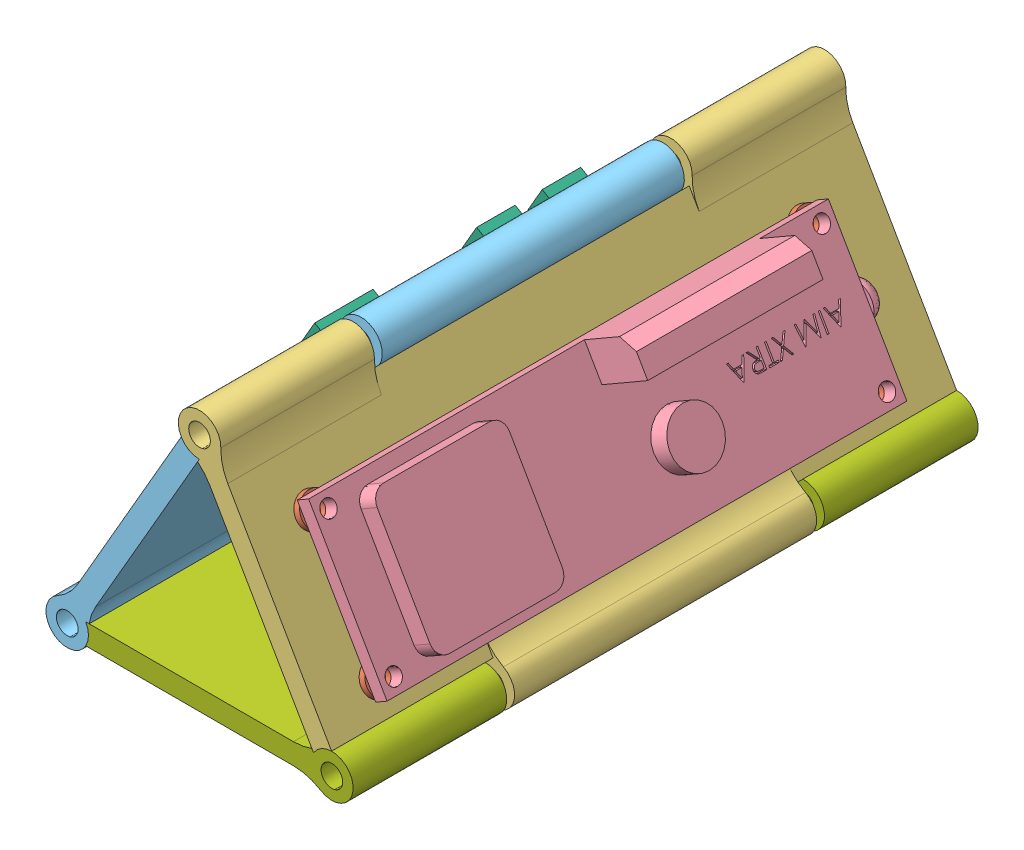
SolidWorks assembly S1B_Fight_Computer_Stack_Assy, configuration Default. Lengths in mm.
Overall size (74.68 77.18 120).
30 component instances, 8 part files, 70 mates.
Components (placement in the parent):
- S1B_6.86mm_Nut_3mm_Hole-7: S1B_6.86mm_Nut_3mm_Hole [Default] at (49.4605 62.5264 50.3494) x (0.433013 -0.75 0.5) z (-0.25 0.433013 0.866025) size (7.92 1.91 6.86)
- S1B_6.86mm_Nut_3mm_Hole-10: S1B_6.86mm_Nut_3mm_Hole [Default] at (38.5881 85.168 145.066) x (-0.433013 0.75 -0.5) z (-0.25 0.433013 0.866025) size (7.92 1.91 6.86)
- S1B_6.86mm_Nut_3mm_Hole-11: S1B_6.86mm_Nut_3mm_Hole [Default] at (36.9383 84.2155 50.3494) x (0.433013 -0.75 -0.5) z (0.25 -0.433013 0.866025) size (7.92 1.91 6.86)
- S1B_6.86mm_Nut_3mm_Hole-12: S1B_6.86mm_Nut_3mm_Hole [Default] at (49.4605 62.5264 145.066) x (0.433013 -0.75 -0.5) z (0.25 -0.433013 0.866025) size (7.92 1.91 6.86)
- S1B_Ruber_Washer_3mm-5: S1B_Ruber_Washer_3mm [Default] at (53.7083 64.9789 145.066) x (-0.5 0.866025 0) z (0 0 1) size (6 1.25 6)
- S1B_Ruber_Washer_3mm-6: S1B_Ruber_Washer_3mm [Default] at (41.1861 86.668 145.066) x (-0.5 0.866025 0) z (0 0 1) size (6 1.25 6)
- S1B_Ruber_Washer_3mm-7: S1B_Ruber_Washer_3mm [Default] at (53.7083 64.9789 50.3494) x (-0.5 0.866025 0) z (0 0 1) size (6 1.25 6)
- S1B_Ruber_Washer_3mm-8: S1B_Ruber_Washer_3mm [Default] at (41.1861 86.668 50.3494) x (-0.5 0.866025 0) z (0 0 1) size (6 1.25 6)
- S1B_Avionics_Stack - AIM-1: S1B_Avionics_Stack - AIM [Default] at (55.5493 84.6273 26.5774) x (-0.5 -0.866025 0) z (0 0 1) size (33.58 52.18 120)
- S1B_AimXtra-1: S1B_AimXtra [Default] at (39.9161 88.8677 47.8094) x (0 0 1) z (-0.5 0.866025 0) size (102.34 16.13 30.12)
- S1B_6.86mm_Nut_3mm_Hole-13: S1B_6.86mm_Nut_3mm_Hole [Default] at (13.2223 66.1787 125.5587) x (0.433013 0.75 -0.5) z (0.25 0.433013 0.866025) size (7.92 1.91 6.86)
- S1B_6.86mm_Nut_3mm_Hole-14: S1B_6.86mm_Nut_3mm_Hole [Default] at (24.7223 86.0973 125.5587) x (0.433013 0.75 -0.5) z (0.25 0.433013 0.866025) size (7.92 1.91 6.86)
- S1B_6.86mm_Nut_3mm_Hole-15: S1B_6.86mm_Nut_3mm_Hole [Default] at (13.2223 66.1787 69.0624) x (0.433013 0.75 0.5) z (-0.25 -0.433013 0.866025) size (7.92 1.91 6.86)
- S1B_6.86mm_Nut_3mm_Hole-16: S1B_6.86mm_Nut_3mm_Hole [Default] at (24.7223 86.0973 67.5587) x (0.433013 0.75 -0.5) z (0.25 0.433013 0.866025) size (7.92 1.91 6.86)
- S1B_Ruber_Washer_3mm-9: S1B_Ruber_Washer_3mm [Default] at (21.3404 88.0498 67.5587) x (0.5 0.866025 0) z (0 0 1) size (6 1.25 6)
- S1B_Ruber_Washer_3mm-10: S1B_Ruber_Washer_3mm [Default] at (9.8404 68.1312 69.0624) x (0.5 0.866025 0) z (0 0 1) size (6 1.25 6)
- S1B_Ruber_Washer_3mm-11: S1B_Ruber_Washer_3mm [Default] at (21.3404 88.0498 125.5587) x (0.5 0.866025 0) z (0 0 1) size (6 1.25 6)
- S1B_Ruber_Washer_3mm-12: S1B_Ruber_Washer_3mm [Default] at (9.8404 68.1312 125.5587) x (0.5 0.866025 0) z (0 0 1) size (6 1.25 6)
- S1B_Avionics_Stack-1: S1B_Avionics_Stack [Default] at (4.7361 84.6273 26.5774) size (33.58 52.18 120)
- S1B_RBP2W-1: S1B_RBP2W [Default] at (13.9471 81.3442 101.7819) x (0 0 -1) z (0.5 0.866025 0) size (65 5.1 31.05)
- S1B_6.86mm_Nut_3mm_Hole-17: S1B_6.86mm_Nut_3mm_Hole [Default] at (44.7248 57.1953 44.9616) x (-0.868623 0 -0.495473) z (-0.495473 0 0.868623) size (7.92 1.91 6.86)
- S1B_6.86mm_Nut_3mm_Hole-18: S1B_6.86mm_Nut_3mm_Hole [Default] at (44.7248 57.1953 59.1316) x (-0.868623 0 -0.495473) z (-0.495473 0 0.868623) size (7.92 1.91 6.86)
- S1B_6.86mm_Nut_3mm_Hole-19: S1B_6.86mm_Nut_3mm_Hole [Default] at (12.4948 57.1953 59.1316) x (-0.868623 0 -0.495473) z (-0.495473 0 0.868623) size (7.92 1.91 6.86)
- S1B_6.86mm_Nut_3mm_Hole-20: S1B_6.86mm_Nut_3mm_Hole [Default] at (12.4948 57.1953 44.9616) x (-0.855922 0 -0.517105) z (-0.517105 0 0.855922) size (7.92 1.91 6.86)
- S1B_Ruber_Washer_3mm-13: S1B_Ruber_Washer_3mm [Default] at (12.4948 52.0403 44.9616) size (6 1.25 6)
- S1B_Ruber_Washer_3mm-14: S1B_Ruber_Washer_3mm [Default] at (44.7248 52.0403 44.9616) size (6 1.25 6)
- S1B_Ruber_Washer_3mm-15: S1B_Ruber_Washer_3mm [Default] at (44.7248 52.0403 59.1316) size (6 1.25 6)
- S1B_Ruber_Washer_3mm-16: S1B_Ruber_Washer_3mm [Default] at (12.4948 52.0403 59.1316) size (6 1.25 6)
- S1B_Avionics_Stack - EasyMini-1: S1B_Avionics_Stack - EasyMini [Default] at (30.1427 40.6218 26.5774) x (-0.5 0.866025 0) z (0 0 1) size (33.58 52.18 120)
- S1B_EZMINI-1: S1B_EZMINI [Default] at (28.7345 50.2403 46.2994) x (1 0 0) z (0 0 -1) size (38.23 12.5 21.18)
Mates (geometry in assembly coordinates):
- Coincident12: coincident anti-aligned: plane of S1B_Avionics_Stack - EasyMini-1 through (30.1427 55.2903 26.5774) normal (0 1 0); plane of 6.86mm_Nut_3mm_Hole-3 through (12.4948 55.2903 59.1316) normal (0 -1 0)
- Concentric4: concentric anti-aligned: cylinder of S1B_Avionics_Stack - EasyMini-1 through (12.4948 61.5329 59.1316) axis (0 -1 0) radius 1.5; cylinder of 6.86mm_Nut_3mm_Hole-3 through (12.4948 55.2903 59.1316) axis (0 1 0) radius 1.5
- Concentric5: concentric anti-aligned: cylinder of S1B_Avionics_Stack - EasyMini-1 through (12.4948 61.5329 44.9616) axis (0 -1 0) radius 1.5; cylinder of 6.86mm_Nut_3mm_Hole-9 through (12.4948 55.2903 44.9616) axis (0 1 0) radius 1.5
- Coincident14: coincident anti-aligned: plane of S1B_Avionics_Stack - EasyMini-1 through (30.1427 55.2903 26.5774) normal (0 1 0); plane of 6.86mm_Nut_3mm_Hole-9 through (12.4948 55.2903 44.9616) normal (0 -1 0)
- Concentric6: concentric anti-aligned: cylinder of S1B_Avionics_Stack - EasyMini-1 through (44.7248 61.5329 59.1316) axis (0 -1 0) radius 1.5; cylinder of 6.86mm_Nut_3mm_Hole-2 through (44.7248 55.2903 59.1316) axis (0 1 0) radius 1.5
- Concentric7: concentric anti-aligned: cylinder of S1B_Avionics_Stack - EasyMini-1 through (44.7248 61.5329 44.9616) axis (0 -1 0) radius 1.5; cylinder of 6.86mm_Nut_3mm_Hole-1 through (44.7248 55.2903 44.9616) axis (0 1 0) radius 1.5
- Coincident15: coincident anti-aligned: plane of S1B_Avionics_Stack - EasyMini-1 through (30.1427 55.2903 26.5774) normal (0 1 0); plane of 6.86mm_Nut_3mm_Hole-2 through (44.7248 55.2903 59.1316) normal (0 -1 0)
- Coincident16: coincident anti-aligned: plane of S1B_Avionics_Stack - EasyMini-1 through (30.1427 55.2903 26.5774) normal (0 1 0); plane of 6.86mm_Nut_3mm_Hole-1 through (44.7248 55.2903 44.9616) normal (0 -1 0)
- Coincident17: coincident anti-aligned: plane of S1B_Avionics_Stack-1 through (17.4394 77.293 26.5774) normal (0.866025 -0.5 0); plane of 6.86mm_Nut_3mm_Hole-5 through (23.0725 87.0498 125.5587) normal (-0.866025 0.5 0)
- Coincident18: coincident anti-aligned: plane of S1B_Avionics_Stack-1 through (17.4394 77.293 26.5774) normal (0.866025 -0.5 0); plane of 6.86mm_Nut_3mm_Hole-4 through (11.5725 67.1312 125.5587) normal (-0.866025 0.5 0)
- Coincident19: coincident anti-aligned: plane of S1B_Avionics_Stack-1 through (17.4394 77.293 26.5774) normal (0.866025 -0.5 0); plane of 6.86mm_Nut_3mm_Hole-8 through (23.0725 87.0498 67.5587) normal (-0.866025 0.5 0)
- Coincident20: coincident anti-aligned: plane of S1B_Avionics_Stack-1 through (17.4394 77.293 26.5774) normal (0.866025 -0.5 0); plane of 6.86mm_Nut_3mm_Hole-6 through (11.5725 67.1312 69.0624) normal (-0.866025 0.5 0)
- Concentric8: concentric anti-aligned: circle of Avionics_Stack-1; cylinder of 6.86mm_Nut_3mm_Hole-8 through (23.0725 87.0498 67.5587) axis (0.866025 -0.5 0) radius 1.5
- Parallel2: parallel anti-aligned: line of S1B_Avionics_Stack-1 through (24.8045 86.0498 63.5993) axis (0.433013 0.75 0.5); line of 6.86mm_Nut_3mm_Hole-8 through (26.4373 89.0677 65.5784) axis (-0.433013 -0.75 -0.5)
- Concentric9: concentric anti-aligned: cylinder of S1B_Avionics_Stack-1 through (18.2035 63.3027 69.0624) axis (-0.866025 0.5 0) radius 2; cylinder of 6.86mm_Nut_3mm_Hole-6 through (11.5725 67.1312 69.0624) axis (0.866025 -0.5 0) radius 1.5
- Parallel3: parallel anti-aligned: line of S1B_Avionics_Stack-1 through (13.3045 66.1312 65.103) axis (0.433013 0.75 0.5); line of 6.86mm_Nut_3mm_Hole-6 through (14.9373 69.1491 67.0821) axis (-0.433013 -0.75 -0.5)
- Concentric10: concentric anti-aligned: cylinder of Avionics_Stack-1; cylinder of 6.86mm_Nut_3mm_Hole-4 through (11.5725 67.1312 125.5587) axis (0.866025 -0.5 0) radius 1.5
- Parallel4: parallel anti-aligned: line of S1B_Avionics_Stack-1 through (13.3045 66.1312 129.5182) axis (-0.433013 -0.75 -0.5); line of 6.86mm_Nut_3mm_Hole-4 through (11.5073 63.2082 127.539) axis (0.433013 0.75 0.5)
- Concentric11: concentric anti-aligned: cylinder of S1B_Avionics_Stack-1 through (29.7035 83.2213 125.5587) axis (-0.866025 0.5 0) radius 2; cylinder of 6.86mm_Nut_3mm_Hole-5 through (23.0725 87.0498 125.5587) axis (0.866025 -0.5 0) radius 1.5
- Parallel5: parallel anti-aligned: line of S1B_Avionics_Stack-1 through (26.519 89.0194 127.5385) axis (-0.433013 -0.75 0.5); line of 6.86mm_Nut_3mm_Hole-5 through (24.7223 86.0973 129.5193) axis (0.433013 0.75 -0.5)
- Coincident29: coincident anti-aligned: plane of S1B_Avionics_Stack - AIM-1 through (43.0625 77.418 26.5774) normal (-0.866025 -0.5 0); plane of 6.86mm_Nut_3mm_Hole-11 through (38.5881 85.168 50.3494) normal (0.866025 0.5 0)
- Coincident30: coincident anti-aligned: plane of S1B_Avionics_Stack - AIM-1 through (43.0625 77.418 26.5774) normal (-0.866025 -0.5 0); plane of 6.86mm_Nut_3mm_Hole-12 through (51.1103 63.4789 145.066) normal (0.866025 0.5 0)
- Coincident31: coincident anti-aligned: plane of S1B_Avionics_Stack - AIM-1 through (43.0625 77.418 26.5774) normal (-0.866025 -0.5 0); plane of 6.86mm_Nut_3mm_Hole-7 through (51.1103 63.4789 50.3494) normal (0.866025 0.5 0)
- Coincident32: coincident anti-aligned: plane of S1B_Avionics_Stack - AIM-1 through (43.0625 77.418 26.5774) normal (-0.866025 -0.5 0); plane of 6.86mm_Nut_3mm_Hole-10 through (38.5881 85.168 145.066) normal (0.866025 0.5 0)
- Concentric13: concentric anti-aligned: cylinder of Avionics_Stack - AIM-1; cylinder of 6.86mm_Nut_3mm_Hole-12 through (51.1103 63.4789 145.066) axis (-0.866025 -0.5 0) radius 1.5
- Concentric14: concentric anti-aligned: cylinder of S1B_Avionics_Stack - AIM-1 through (32.3529 81.5681 145.066) axis (0.866025 0.5 0) radius 1.75; circle of 6.86mm_Nut_3mm_Hole-10
- Concentric15: concentric aligned: circle of Avionics_Stack - AIM-1; circle of 6.86mm_Nut_3mm_Hole-11
- Concentric16: concentric aligned: circle of Avionics_Stack - AIM-1; circle of 6.86mm_Nut_3mm_Hole-7
- Parallel6: parallel anti-aligned: line of S1B_Avionics_Stack - AIM-1 through (47.4472 65.3235 48.3696) axis (0.433013 -0.75 -0.5); line of 6.86mm_Nut_3mm_Hole-7 through (49.4605 62.5264 46.3887) axis (-0.433013 0.75 0.5)
- Parallel7: parallel anti-aligned: line of S1B_Avionics_Stack - AIM-1 through (34.925 87.0126 48.3696) axis (0.433013 -0.75 -0.5); line of 6.86mm_Nut_3mm_Hole-11 through (36.9383 84.2155 46.3887) axis (-0.433013 0.75 0.5)
- Parallel8: parallel aligned: line of S1B_Avionics_Stack - AIM-1 through (34.925 87.0126 147.0457) axis (0 0 -1); line of 6.86mm_Nut_3mm_Hole-10 through (35.2233 87.186 147.0463) axis (0 0 -1)
- Parallel9: parallel anti-aligned: line of S1B_Avionics_Stack - AIM-1 through (49.1617 62.3539 149.0254) axis (-0.433013 0.75 -0.5); line of 6.86mm_Nut_3mm_Hole-12 through (47.7455 65.4969 147.0463) axis (0.433013 -0.75 0.5)
- Concentric17: concentric aligned: cylinder of S1B_Avionics_Stack - AIM-1 through (55.5493 55.2903 156.5774) axis (0 0 -1) radius 2.0875; cylinder of S1B_Avionics_Stack - EasyMini-1 through (55.5493 55.2903 156.5774) axis (0 0 -1) radius 2.0875
- Coincident37: coincident anti-aligned: cylinder of S1B_Avionics_Stack-1 through (4.7361 55.2903 156.5774) axis (0 0 -1) radius 2.0875; circle of Avionics_Stack - EasyMini-1
- Concentric18: concentric aligned: cylinder of S1B_Avionics_Stack - AIM-1 through (30.1427 99.2958 156.5774) axis (0 0 -1) radius 2.0875; cylinder of S1B_Avionics_Stack-1 through (30.1427 99.2958 156.5774) axis (0 0 -1) radius 2.0875
- Coincident40: coincident aligned: plane of Ruber_Washer_3mm-1 through (21.3404 88.0498 67.5587) normal (0.866025 -0.5 0); plane of Ruber_Washer_3mm-3 through (21.3404 88.0498 125.5587) normal (0.866025 -0.5 0)
- Coincident41: coincident aligned: plane of Ruber_Washer_3mm-2 through (9.8404 68.1312 69.0624) normal (0.866025 -0.5 0); plane of Ruber_Washer_3mm-4 through (9.8404 68.1312 125.5587) normal (0.866025 -0.5 0)
- Coincident42: coincident aligned: plane of Ruber_Washer_3mm-3 through (21.3404 88.0498 125.5587) normal (0.866025 -0.5 0); plane of Ruber_Washer_3mm-4 through (9.8404 68.1312 125.5587) normal (0.866025 -0.5 0)
- Coincident43: coincident anti-aligned: plane of S1B_Avionics_Stack-1 through (15.7074 78.293 156.5774) normal (-0.866025 0.5 0); plane of Ruber_Washer_3mm-4 through (9.8404 68.1312 125.5587) normal (0.866025 -0.5 0)
- Concentric19: concentric aligned: circle of Avionics_Stack-1; circle of Ruber_Washer_3mm-1
- Concentric20: concentric aligned: circle of Avionics_Stack-1; circle of Ruber_Washer_3mm-3
- Concentric21: concentric aligned: circle of Avionics_Stack-1; circle of Ruber_Washer_3mm-4
- Concentric22: concentric aligned: circle of Avionics_Stack-1; circle of Ruber_Washer_3mm-2
- Concentric26: concentric anti-aligned: cylinder of RBP2W-1 through (8.7579 68.7562 125.5587) axis (-0.866025 0.5 0) radius 1.5; cylinder of Ruber_Washer_3mm-4 through (8.7579 68.7562 125.5587) axis (0.866025 -0.5 0) radius 1.55
- Coincident46: coincident anti-aligned: plane of RBP2W-1 through (15.506 80.4442 101.7819) normal (0.866025 -0.5 0); plane of Ruber_Washer_3mm-1 through (20.2579 88.6748 67.5587) normal (-0.866025 0.5 0)
- Concentric27: concentric aligned: cylinder of S1B_Avionics_Stack-1 through (29.7035 83.2213 67.5587) axis (-0.866025 0.5 0) radius 2; circle of RBP2W-1
- Coincident47: coincident aligned: plane of Ruber_Washer_3mm-7 through (53.7083 64.9789 50.3494) normal (0.866025 0.5 0); plane of Ruber_Washer_3mm-8 through (41.1861 86.668 50.3494) normal (0.866025 0.5 0)
- Coincident48: coincident aligned: plane of Ruber_Washer_3mm-5 through (53.7083 64.9789 145.066) normal (0.866025 0.5 0); plane of Ruber_Washer_3mm-6 through (41.1861 86.668 145.066) normal (0.866025 0.5 0)
- Coincident49: coincident aligned: plane of Ruber_Washer_3mm-6 through (41.1861 86.668 145.066) normal (0.866025 0.5 0); plane of Ruber_Washer_3mm-7 through (53.7083 64.9789 50.3494) normal (0.866025 0.5 0)
- Coincident50: coincident anti-aligned: plane of S1B_Avionics_Stack - AIM-1 through (44.5781 78.293 156.5774) normal (0.866025 0.5 0); plane of Ruber_Washer_3mm-8 through (40.1036 86.043 50.3494) normal (-0.866025 -0.5 0)
- Concentric28: concentric anti-aligned: circle of Avionics_Stack - AIM-1; circle of Ruber_Washer_3mm-8
- Concentric29: concentric anti-aligned: circle of Avionics_Stack - AIM-1; circle of Ruber_Washer_3mm-7
- Concentric30: concentric anti-aligned: circle of Avionics_Stack - AIM-1; circle of Ruber_Washer_3mm-6
- Concentric31: concentric anti-aligned: circle of Avionics_Stack - AIM-1; circle of Ruber_Washer_3mm-5
- Concentric32: concentric aligned: cylinder of S1B_Avionics_Stack - AIM-1 through (32.3529 81.5681 50.3494) axis (0.866025 0.5 0) radius 1.75; cylinder of AimXtra-1 through (43.3858 87.938 50.3494) axis (0.866025 0.5 0) radius 1.5
- Coincident55: coincident anti-aligned: plane of AimXtra-1 through (39.9161 88.8677 47.8094) normal (-0.866025 -0.5 0); plane of Ruber_Washer_3mm-6 through (41.1861 86.668 145.066) normal (0.866025 0.5 0)
- Concentric33: concentric aligned: cylinder of S1B_Avionics_Stack - AIM-1 through (44.8751 59.879 145.066) axis (0.866025 0.5 0) radius 1.75; cylinder of AimXtra-1 through (55.908 66.2489 145.066) axis (0.866025 0.5 0) radius 1.5
- Coincident56: coincident aligned: plane of Ruber_Washer_3mm-10 through (44.7248 53.2903 44.9616) normal (0 1 0); plane of Ruber_Washer_3mm-11 through (44.7248 53.2903 59.1316) normal (0 1 0)
- Coincident57: coincident aligned: plane of Ruber_Washer_3mm-9 through (12.4948 53.2903 44.9616) normal (0 1 0); plane of Ruber_Washer_3mm-13 through (12.4948 53.2903 59.1316) normal (0 1 0)
- Coincident58: coincident aligned: plane of Ruber_Washer_3mm-9; plane of Ruber_Washer_3mm-11 through (44.7248 53.2903 59.1316) normal (0 1 0)
- Coincident59: coincident anti-aligned: plane of S1B_Avionics_Stack - EasyMini-1 through (30.1427 53.2903 156.5774) normal (0 -1 0); plane of Ruber_Washer_3mm-11 through (44.7248 53.2903 59.1316) normal (0 1 0)
- Concentric34: concentric anti-aligned: circle of Avionics_Stack - EasyMini-1; circle of Ruber_Washer_3mm-10
- Concentric35: concentric anti-aligned: circle of Avionics_Stack - EasyMini-1; circle of Ruber_Washer_3mm-11
- Concentric36: concentric anti-aligned: circle of Avionics_Stack - EasyMini-1; circle of Ruber_Washer_3mm-13
- Concentric37: concentric anti-aligned: circle of Avionics_Stack - EasyMini-1; circle of Ruber_Washer_3mm-9
- Concentric38: concentric aligned: cylinder of EZMINI-1 through (44.7248 52.0403 59.1316) axis (0 -1 0) radius 1.5; cylinder of Ruber_Washer_3mm-11 through (44.7248 53.2903 59.1316) axis (0 -1 0) radius 1.55
- Coincident60: coincident anti-aligned: plane of EZMINI-1 through (28.7345 52.0403 46.2994) normal (0 1 0); plane of Ruber_Washer_3mm-9 through (12.4948 52.0403 44.9616) normal (0 -1 0)
- Concentric39: concentric aligned: cylinder of EZMINI-1 through (12.4948 52.0403 44.9616) axis (0 -1 0) radius 1.5; cylinder of Ruber_Washer_3mm-9 through (12.4948 53.2903 44.9616) axis (0 -1 0) radius 1.55
- Coincident61: coincident aligned: plane of S1B_Avionics_Stack-1 through (4.7361 84.6273 156.5774) normal (0 0 1); plane of S1B_Avionics_Stack - EasyMini-1 through (30.1427 40.6218 156.5774) normal (0 0 1)
- Coincident62: coincident aligned: plane of S1B_Avionics_Stack - AIM-1 through (55.5493 84.6273 156.5774) normal (0 0 1); plane of S1B_Avionics_Stack-1 through (4.7361 84.6273 156.5774) normal (0 0 1)
